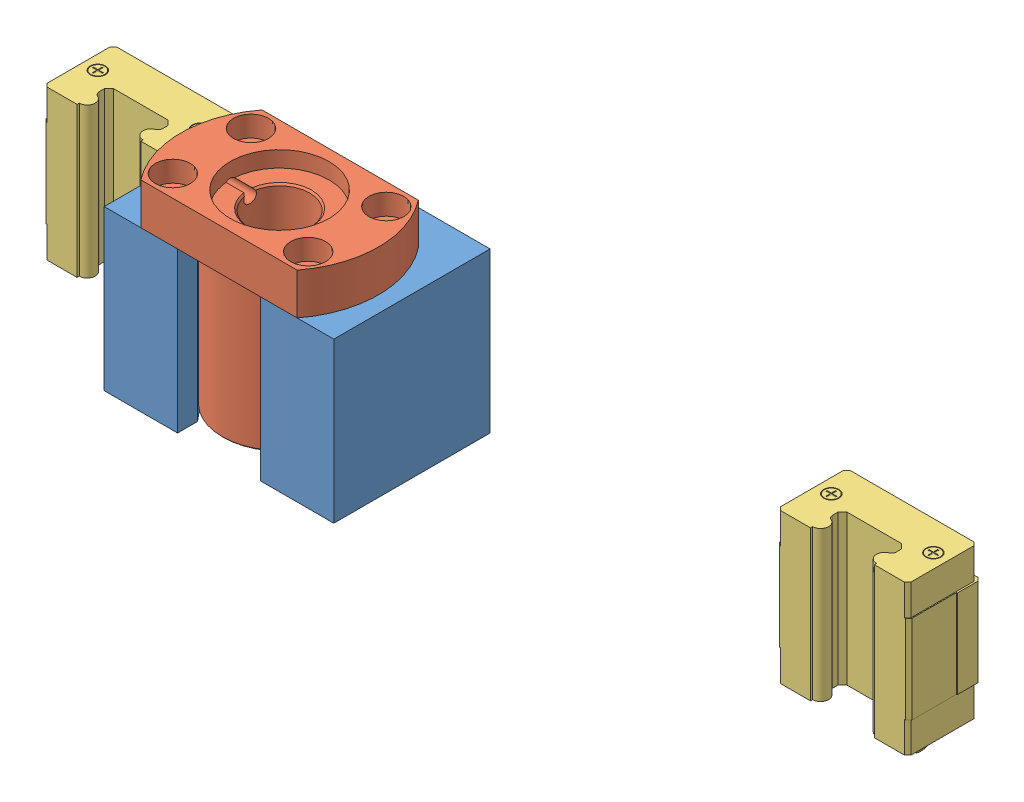
SolidWorks assembly Schlitten_y.Achse, configuration Standard. Lengths in mm.
Overall size (272 73 49).
4 component instances, 3 part files, 8 mates.
Components (placement in the parent):
- bnfb2010c_30_2_14b-1: bnfb2010c_30_2_14b [Standard] at (-99.5824 21.6887 259.7804) x (1 0 0) z (0 1 0) size (72 49 50)
- y.2-1: y.2 [Standard] at (-99.5824 -773.0613 259.7804) x (0 1 0) z (0 0 1) size (58.5 62 38)
- y.2.1.1.1-1: y.2.1.1.1 [Standard] at (-157.5824 23.1887 260.7804) x (-1 0 0) z (0 -1 0) size (42 22.5 60)
- y.2.1.1.1-2: y.2.1.1.1 [Standard] at (72.4176 23.1887 260.7804) x (-1 0 0) z (0 -1 0) size (42 22.5 60)
Mates (geometry in assembly coordinates):
- Deckungsgleich4: coincident anti-aligned: plane of bnfb2010c_30_2_14b-1 through (-99.5824 46.6887 259.7804) normal (0 1 0); plane of y.2-1 through (-99.5824 46.6887 259.7804) normal (0 -1 0)
- Konzentrisch1: concentric aligned: cylinder of bnfb2010c_30_2_14b-1 through (-99.5824 46.6887 259.7804) axis (0 1 0) radius 18.2; cylinder of y.2-1 through (-99.5824 24.1887 259.7804) axis (0 1 0) radius 18
- Abstand7: distance = 157 mm aligned: plane of y.2.1.1.1-2 through (93.4176 9.3887 233.7804) normal (1 0 0); plane of bnfb2010c_30_2_14b-1 through (-63.5824 46.6887 278.7804) normal (1 0 0)
- Deckungsgleich17: coincident aligned: plane of y.2.1.1.1-1 through (-146.5824 9.3887 232.7804) normal (0 0 -1); plane of y.2.1.1.1-2 through (52.4176 9.3887 232.7804) normal (0 0 -1)
- Abstand8: distance = 1 mm anti-aligned: plane of y.2.1.1.1-1 through (-136.5824 9.3887 233.7804) normal (1 0 0); plane of bnfb2010c_30_2_14b-1 through (-135.5824 46.6887 229.7804) normal (-1 0 0)
- Deckungsgleich19: coincident aligned: plane of y.2.1.1.1-1 through (-157.5824 -0.3113 255.2804) normal (0 -1 0); plane of y.2.1.1.1-2 through (72.4176 -0.3113 255.2804) normal (0 -1 0)
- Abstand9: distance = 3 mm aligned: plane of bnfb2010c_30_2_14b-1 through (-63.5824 46.6887 229.7804) normal (0 0 -1); plane of y.2.1.1.1-1 through (-146.5824 9.3887 232.7804) normal (0 0 -1)
- Abstand10: distance = 3 mm aligned: plane of bnfb2010c_30_2_14b-1 through (-99.5824 -3.3113 259.7804) normal (0 -1 0); plane of y.2.1.1.1-1 through (-157.5824 -0.3113 255.2804) normal (0 -1 0)
